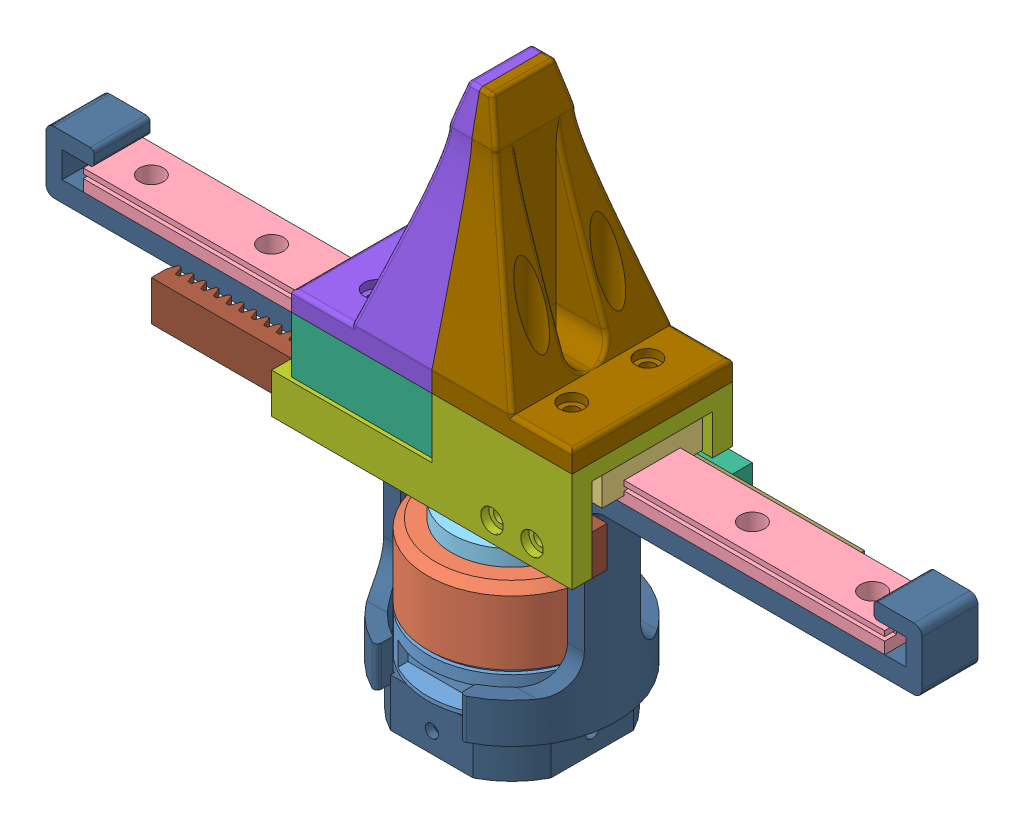
SolidWorks assembly MyGripper, configuration 默认. Lengths in mm.
Overall size (218.6 138.06 52.44).
17 component instances, 14 part files, 36 mates.
Components (placement in the parent):
- 3510-1: 3510 [默认] at origin size (52.44 31.5 52.44)
  - 3510定子-1: 3510定子 [默认] at origin size (42 27.5 42)
  - 3510转子-1: 3510转子 [默认] at (0 29 0) x (-0.956343 0 0.292248) z (0.292248 0 0.956343) size (42 19 42)
- MGW9滑轨模组-2: MGW9滑轨模组 [默认] at (0 53 7) size (200 9 25) (flexible)
  - MGW9C滑块-1: MGW9C滑块 [默认] at (-35 1.9 5.5) size (31.2 7.1 25)
  - MGW9导轨-1: MGW9导轨 [默认] at (-100 0 0) size (200 5.2 14)
  - MGW9C滑块-2: MGW9C滑块 [默认] at (35 1.9 -19.5) x (-1 0 0) z (0 0 -1) size (31.2 7.1 25)
- 转子齿轮连接件-1: 转子齿轮连接件 [默认] at (0 29 0) x (0.956343 0 -0.292248) z (0.292248 0 0.956343) size (30 22 30)
- 滑块手指连接件-1: 滑块手指连接件 [默认] at (-35 62 20) size (75 25 40)
- 滑块手指连接件2-1: 滑块手指连接件2 [默认] at (35 62 -20) x (-1 0 0) z (0 0 -1) size (75 25 40)
- 手指-1: 手指 [默认] at (0 66 -20) x (-1 0 0) z (0 0 -1) size (35 60.06 42.71)
- 镜向手指-2: 镜向手指 [默认] at (0 66 -20) size (35 60.06 42.71)
- 夹爪外壳-1: 夹爪外壳 [默认] at (0 -2 0) size (218.6 75.5 49.28)
- 齿条-1: 齿条 [默认] at (35 51 15) x (-1 0 0) z (0 0 1) size (110 10 6)
- 齿条2-1: 齿条2 [默认] at (-35 51 -15) x (1 0 0) z (0 0 -1) size (108 10 6)
- spur gear_gb-1: spur gear_gb [GB - Spur gear 1M 20T 20PA 10FW ---S20B16H18L10.0N] at (0 41.0001 0) x (0 1 0) z (0.158015 0 0.987437) size (18 21.8 21.8)
- 外壳内挡块-1: 外壳内挡块 [默认] at (0 -2 0) x (-1 0 0) z (0 0 1) size (28 9.5 28)
Mates (geometry in assembly coordinates):
- 同心1: concentric anti-aligned: circle of 3510-1/3510转子-1; circle of 转子齿轮连接件-1
- 重合1: coincident anti-aligned: plane of 3510-1/3510转子-1 through (0 29 0) normal (0 1 0); plane of 转子齿轮连接件-1 through (0 29 0) normal (0 -1 0)
- 同心2: concentric aligned: cylinder of 3510-1/3510转子-1 through (-7.7947 12 -1.8006) axis (0 1 0) radius 1.5; cylinder of 转子齿轮连接件-1 through (-7.7947 28 -1.8006) axis (0 1 0) radius 1.6
- 同心4: concentric anti-aligned: cylinder of MGW9滑轨模组-2/MGW9导轨-1 through (0 27.2 0) axis (0 1 0) radius 1.75; cylinder of 转子齿轮连接件-1 through (0 33 0) axis (0 -1 0) radius 15
- 重合8: coincident anti-aligned: plane of 3510-1/3510定子-1 through (0 0 0) normal (0 -1 0)
- 同心5: concentric anti-aligned: circle of 3510-1/3510定子-1
- 平行4: parallel aligned: plane of 3510-1/3510定子-1 through (0 0 16) normal (0 0 1)
- 平行5: parallel aligned: plane of 3510-1/3510定子-1 through (0 0 16) normal (0 0 1); plane of MGW9滑轨模组-2/MGW9导轨-1 through (-100 58.2 7) normal (0 0 1)
- 同心6: concentric aligned: cylinder of MGW9滑轨模组-2/MGW9C滑块-1 through (-14.4 60 9.5) axis (0 1 0) radius 1.5; cylinder of 滑块手指连接件-1 through (-14.4 60 9.5) axis (0 1 0) radius 1.6
- 同心7: concentric aligned: cylinder of MGW9滑轨模组-2/MGW9C滑块-1 through (-14.4 60 -9.5) axis (0 1 0) radius 1.5; cylinder of 滑块手指连接件-1 through (-14.4 60 -9.5) axis (0 1 0) radius 1.6
- 重合18: coincident anti-aligned: plane of MGW9滑轨模组-2/MGW9C滑块-1 through (-35 62 12.5) normal (0 1 0); plane of 滑块手指连接件-1 through (-35 62 20) normal (0 -1 0)
- 同心9: concentric aligned: cylinder of 滑块手指连接件2-1 through (24.5083 60 9.5) axis (0 1 0) radius 1.6; cylinder of MGW9滑轨模组-3/MGW9C滑块-1 through (25.65 66 10.5) axis (0 1 0) radius 1.5
- 重合23: coincident anti-aligned: plane of 滑块手指连接件-1 through (-35 66 20) normal (0 1 0); plane of 手指-1 through (0 66 -20) normal (0 -1 0)
- 重合27: coincident anti-aligned: plane of 3510-1/3510定子-1 through (0 0 0) normal (0 -1 0); plane of 夹爪外壳-1 through (0 0 0) normal (0 1 0)
- 同心11: concentric aligned: cylinder of 3510-1/3510定子-1 through (-12.7279 4 12.7279) axis (0 -1 0) radius 1.5; cylinder of 夹爪外壳-1 through (-12.7279 0 12.7279) axis (0 -1 0) radius 1.6
- 同心12: concentric aligned: cylinder of 3510-1/3510定子-1 through (12.7279 4 12.7279) axis (0 -1 0) radius 1.5; cylinder of 夹爪外壳-1 through (12.7279 0 12.7279) axis (0 -1 0) radius 1.6
- 宽度4: width aligned: plane of 滑块手指连接件-1 through (-35 66 -20) normal (0 0 -1); plane of 手指-1 through (-35 66 20) normal (0 0 1); plane of 滑块手指连接件-1 through (0 71 -20) normal (0 0 -1); plane of 手指-1 through (0 71 20) normal (0 0 1)
- 重合36: coincident anti-aligned: plane of MGW9滑轨模组-3/MGW9导轨-1 through (100 56 -9) normal (0 -1 0); plane of 夹爪外壳-1 through (0 53 0) normal (0 1 0)
- 同心15: concentric anti-aligned: cylinder of 滑块手指连接件2-1 through (25 46 18) axis (0 0 1) radius 2.8; cylinder of 齿条-1 through (25 46 21.25) axis (0 0 -1) radius 1.6
- 同心16: concentric anti-aligned: cylinder of 滑块手指连接件2-1 through (15 46 18) axis (0 0 1) radius 2.8; cylinder of 齿条-1 through (15 46 21.25) axis (0 0 -1) radius 1.6
- 重合38: coincident anti-aligned: plane of 滑块手指连接件2-1 through (35 41 15) normal (0 0 -1); plane of 齿条-1 through (35 41 15) normal (0 0 1)
- 同心17: concentric anti-aligned: cylinder of 滑块手指连接件-1 through (-25 46 -5) axis (0 0 -1) radius 1.6; cylinder of 齿条2-1 through (-25 46 -21.25) axis (0 0 1) radius 1.6
- 同心18: concentric anti-aligned: cylinder of 滑块手指连接件-1 through (-15 46 -5) axis (0 0 -1) radius 1.6; cylinder of 齿条2-1 through (-15 46 -21.25) axis (0 0 1) radius 1.6
- 重合39: coincident anti-aligned: plane of 滑块手指连接件-1 through (-35 41 -15) normal (0 0 1); plane of 齿条2-1 through (-35 41 -15) normal (0 0 -1)
- 重合40: coincident anti-aligned: plane of MGW9滑轨模组-2/MGW9导轨-1 through (-100 53 7) normal (0 -1 0); plane of 夹爪外壳-1 through (0 53 0) normal (0 1 0)
- 同心19: concentric anti-aligned: cylinder of 滑块手指连接件-1 through (-24.4 60 9.5) axis (0 1 0) radius 1.6; cylinder of 手指-1 through (-24.4 111 9.5) axis (0 -1 0) radius 1.75
- 宽度5: width anti-aligned: plane of MGW9滑轨模组-2/MGW9导轨-1 through (-100 58.2 7) normal (-1 0 0); plane of 手指-1 through (0 71 -20) normal (1 0 0); plane of 手指-1 through (-35 71 -20) normal (-1 0 0)
- 同心20: concentric aligned: cylinder of 转子齿轮连接件-1 through (0 51 0) axis (0 -1 0) radius 5; cylinder of spur gear_gb-1 through (0 59.0001 0) axis (0 -1 0) radius 5
- 重合41: coincident anti-aligned: plane of 转子齿轮连接件-1 through (0 33 0) normal (0 1 0); plane of spur gear_gb-1 through (0 33 0) normal (0 -1 0)
- 同心21: concentric anti-aligned: cylinder of 滑块手指连接件2-1 through (14.4 60 9.5) axis (0 1 0) radius 1.6; cylinder of 镜向手指-2 through (14.4 111 9.5) axis (0 -1 0) radius 1.75
- 同心22: concentric anti-aligned: cylinder of 滑块手指连接件2-1 through (24.4 60 -9.5) axis (0 1 0) radius 1.6; cylinder of 镜向手指-2 through (24.4 111 -9.5) axis (0 -1 0) radius 1.75
- 重合42: coincident anti-aligned: plane of 滑块手指连接件2-1 through (35 66 -20) normal (0 1 0); plane of 镜向手指-2 through (0 66 -20) normal (0 -1 0)
- RackPinionMate1: rack pinion = 17.498 mm: line of 齿条2-1 through (6.1992 41 -9.0004) axis (-1 0 0); circle of spur gear_gb-1
- 重合43: coincident anti-aligned: plane of 夹爪外壳-1 through (0 -2 0) normal (0 -1 0); plane of 外壳内挡块-1 through (0 -2 0) normal (0 1 0)
- 同心24: concentric aligned: cylinder of 3510-1/3510定子-1 through (0 -1.5 0) axis (0 1 0) radius 9; cylinder of 外壳内挡块-1 through (0 -11.5 0) axis (0 1 0) radius 7.5
- 平行6: parallel anti-aligned: plane of 夹爪外壳-1 through (-9.0139 -12 15) normal (0 0 -1); plane of 外壳内挡块-1 through (-8 -11.5 14) normal (0 0 1)
